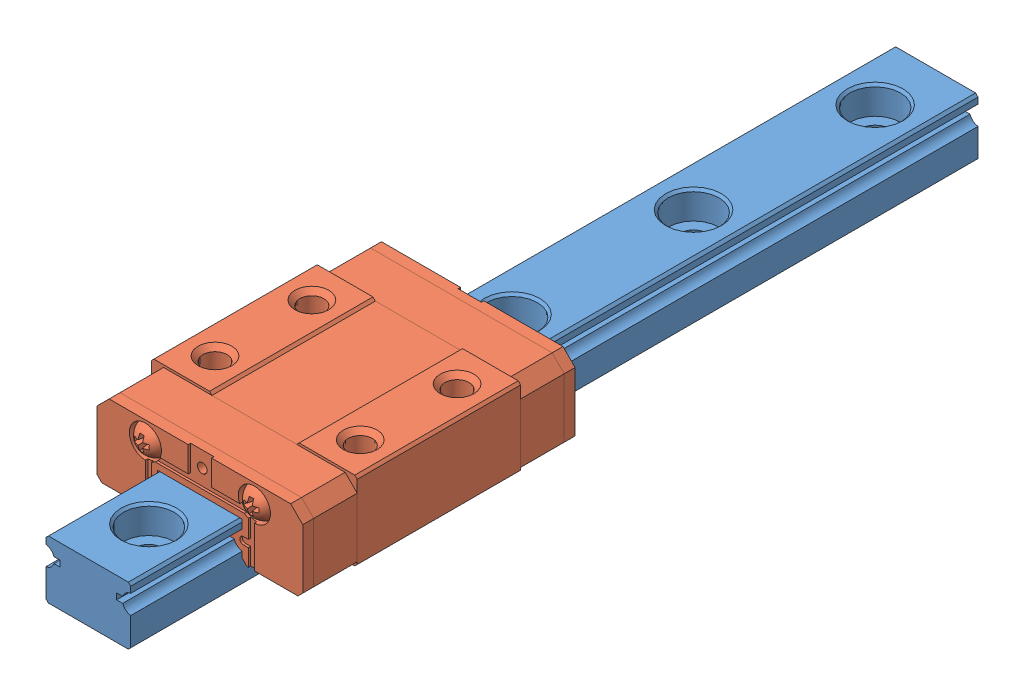
SolidWorks assembly MGN7 with rail, configuration MGN7C 150 mm. Lengths in mm.
Overall size (17 8.1 70).
2 component instances, 2 part files, 2 mates.
Components (placement in the parent):
- MGN7 rail-1: MGN7 rail [70 mm] at origin size (7 4.8 70)
- MGN7C-1: MGN7C [MGN7C] at (0 2.45 49.537) size (17 6.5 23.31)
Mates (geometry in assembly coordinates):
- Coincident1: coincident anti-aligned: plane of MGN7 rail-1 through (-3.3 2.4 70) normal (0 1 0); plane of MGN7C-1 through (0 2.4 56.287) normal (0 -1 0)
- Coincident2: coincident anti-aligned: plane of MGN7 rail-1 through (-3.5 -2.2 70) normal (-1 0 0); plane of MGN7C-1 through (-3.5 2.45 56.287) normal (1 0 0)
